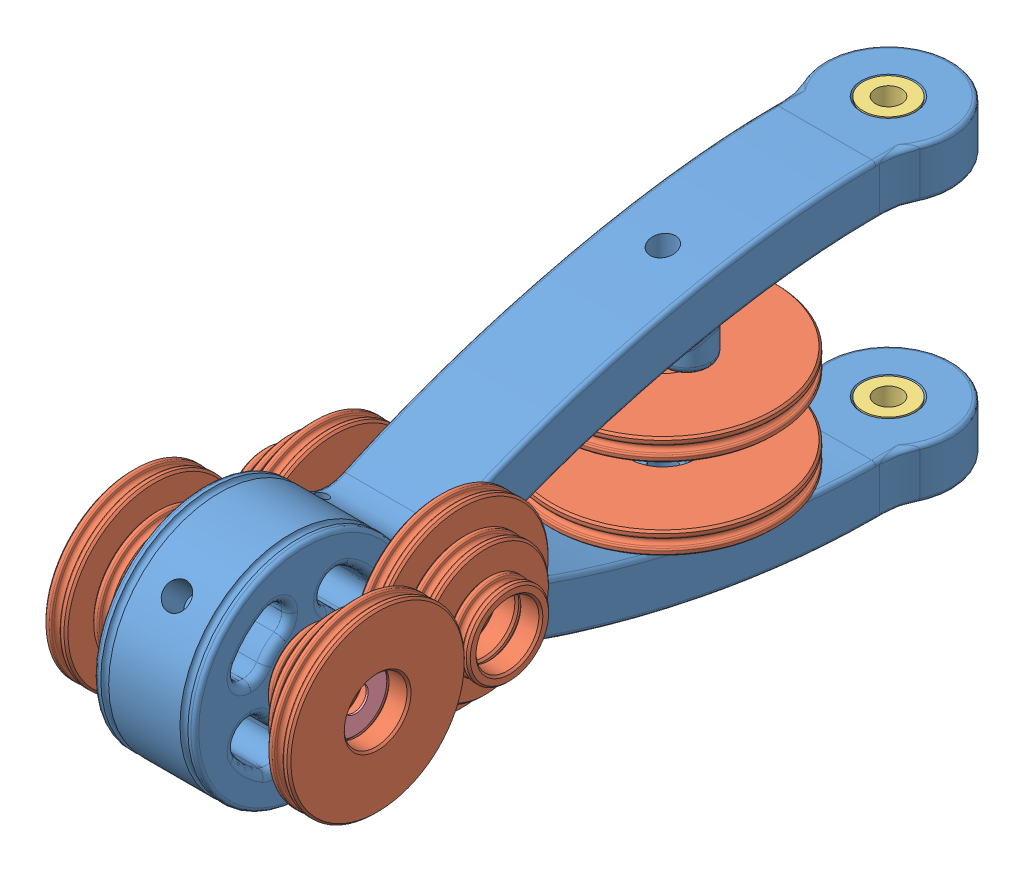
SolidWorks assembly Assem3^assembled_4dof_arm, configuration Default. Lengths in mm.
Overall size (34.5 42.48 102.6).
23 component instances, 4 part files, 25 mates.
Components (placement in the parent):
- joint1-1: joint1 [Default] at origin size (16 42.48 102)
- Pulley_configurable-1: Pulley_configurable [p1_bearing] at (8.0161 0 -16.65) x (0 -0.797414 -0.603433) z (0 0.603433 -0.797414) size (22.4 2.78 22.4)
- Pulley_configurable-3: Pulley_configurable [p2_bearing] at (11.0482 0 -16.65) x (0 0.936654 0.350255) z (0 -0.350255 0.936654) size (16.4 2.78 16.4)
- Pulley_configurable-6: Pulley_configurable [p3_bearing] at (14.0803 0 -16.65) x (0 0.732668 0.680586) z (0 -0.680586 0.732668) size (10.4 2.78 10.4)
- Pulley_configurable-7: Pulley_configurable [p3_bearing] at (8.0161 0 0) x (0 -0.534541 0.845142) z (0 -0.845142 -0.534541) size (10.4 2.78 10.4)
- Pulley_configurable-8: Pulley_configurable [p2_bearing] at (11.0482 0 0) x (0 0.972645 0.232297) z (0 -0.232297 0.972645) size (16.4 2.78 16.4)
- Pulley_configurable-9: Pulley_configurable [p1_bearing] at (14.0803 0 0) x (0 0.377137 0.926157) z (0 -0.926157 0.377137) size (22.4 2.78 22.4)
- 6377K490_ULTRA-LOW-FRICTION DRY-RUNNING SLEEVE BEARING-1: 6377K490_ULTRA-LOW-FRICTION DRY-RUNNING SLEEVE BEARING [6377K49] at (0 16.425 -80) x (1 0 0) z (0 -1 0) size (6.38 6.38 6.35)
- 6377K490_ULTRA-LOW-FRICTION DRY-RUNNING SLEEVE BEARING-2: 6377K490_ULTRA-LOW-FRICTION DRY-RUNNING SLEEVE BEARING [6377K49] at (0 -16.425 -80) x (1 0 0) z (0 -1 0) size (6.38 6.38 6.35)
- Pulley_configurable-13: Pulley_configurable [p0_bearing] at (0 5.1069 -51.5) x (0.969458 0 0.245256) z (-0.245256 0 0.969458) size (28.4 2.78 28.4)
- Pulley_configurable-14: Pulley_configurable [p0_bearing] at (0 -5.1069 -51.5) x (0.969458 0 0.245256) z (-0.245256 0 0.969458) size (28.4 2.78 28.4)
- 10thouspacer_3125shaft-1: 10thouspacer_3125shaft [Default] at (9.4051 0 0) x (0 -0.052278 -0.998633) z (1 0 0) size (7.87 7.87 0.25)
- 10thouspacer_3125shaft-2: 10thouspacer_3125shaft [Default] at (12.4373 0 0) x (0 -0.167406 -0.985888) z (1 0 0) size (7.87 7.87 0.25)
- 10thouspacer_3125shaft-3: 10thouspacer_3125shaft [Default] at (6.373 0 0) x (0 -0.167406 -0.985888) z (1 0 0) size (7.87 7.87 0.25)
- Pulley_configurable-15: Pulley_configurable [p1_bearing] at (-14.0803 0 0) x (0 0.377137 0.926157) z (0 0.926157 -0.377137) size (22.4 2.78 22.4)
- Pulley_configurable-16: Pulley_configurable [p3_bearing] at (-14.0803 0 -16.65) x (0 0.732668 0.680586) z (0 0.680586 -0.732668) size (10.4 2.78 10.4)
- Pulley_configurable-17: Pulley_configurable [p2_bearing] at (-11.0482 0 0) x (0 0.972645 0.232297) z (0 0.232297 -0.972645) size (16.4 2.78 16.4)
- Pulley_configurable-18: Pulley_configurable [p2_bearing] at (-11.0482 0 -16.65) x (0 0.936654 0.350255) z (0 0.350255 -0.936654) size (16.4 2.78 16.4)
- Pulley_configurable-19: Pulley_configurable [p1_bearing] at (-8.0161 0 -16.65) x (0 -0.797414 -0.603433) z (0 -0.603433 0.797414) size (22.4 2.78 22.4)
- Pulley_configurable-20: Pulley_configurable [p3_bearing] at (-8.0161 0 0) x (0 -0.534541 0.845142) z (0 0.845142 0.534541) size (10.4 2.78 10.4)
- 10thouspacer_3125shaft-4: 10thouspacer_3125shaft [Default] at (-12.6913 0 0) x (0 -0.167406 -0.985888) z (1 0 0) size (7.87 7.87 0.25)
- 10thouspacer_3125shaft-5: 10thouspacer_3125shaft [Default] at (-9.6591 0 0) x (0 -0.052278 -0.998633) z (1 0 0) size (7.87 7.87 0.25)
- 10thouspacer_3125shaft-6: 10thouspacer_3125shaft [Default] at (-6.627 0 0) x (0 -0.167406 -0.985888) z (1 0 0) size (7.87 7.87 0.25)
Mates (geometry in assembly coordinates):
- Concentric20: concentric: cylinder of joint1-1 through (6.373 0 -16.65) axis (-1 0 0) radius 1.5875; cylinder of Pulley_configurable-6 through (14.0803 0 -16.65) axis (1 0 0) radius 3.9688
- Concentric21: concentric: cylinder of joint1-1 through (6.373 0 0) axis (-1 0 0) radius 1.5875; cylinder of Pulley_configurable-9 through (14.0803 0 0) axis (1 0 0) radius 3.9688
- Concentric31: concentric: cylinder of joint1-1 through (0 19.6 -80) axis (0 -1 0) radius 3.175; cylinder of 6377K490_ULTRA-LOW-FRICTION DRY-RUNNING SLEEVE BEARING-1 through (0 13.25 -80) axis (0 1 0) radius 3.1877
- Concentric32: concentric: cylinder of joint1-1 through (0 -19.6 -80) axis (0 1 0) radius 3.175; cylinder of 6377K490_ULTRA-LOW-FRICTION DRY-RUNNING SLEEVE BEARING-2 through (0 -19.6 -80) axis (0 1 0) radius 3.1877
- Concentric62: concentric: cylinder of joint1-1 through (0 -19.602 -51.5) axis (0 1 0) radius 1.5875; cylinder of Pulley_configurable-13 through (0 5.1069 -51.5) axis (0 -1 0) radius 3.9688
- Concentric3: concentric: cylinder of Pulley_configurable-1 through (8.0161 0 -16.65) axis (1 0 0) radius 3.9688; cylinder of Pulley_configurable-3 through (11.0482 0 -16.65) axis (1 0 0) radius 3.9688
- Concentric4: concentric: cylinder of Pulley_configurable-3 through (11.0482 0 -16.65) axis (1 0 0) radius 3.9688; cylinder of Pulley_configurable-6 through (14.0803 0 -16.65) axis (1 0 0) radius 3.9688
- Concentric11: concentric: cylinder of Pulley_configurable-7 through (8.0161 0 0) axis (1 0 0) radius 3.9688; cylinder of Pulley_configurable-8 through (11.0482 0 0) axis (1 0 0) radius 3.9688
- Concentric10: concentric: cylinder of Pulley_configurable-8 through (11.0482 0 0) axis (1 0 0) radius 3.9688; cylinder of Pulley_configurable-9 through (14.0803 0 0) axis (1 0 0) radius 3.9688
- Concentric57: concentric: cylinder of Pulley_configurable-13 through (0 5.1069 -51.5) axis (0 -1 0) radius 3.9688; cylinder of Pulley_configurable-14 through (0 -5.1069 -51.5) axis (0 -1 0) radius 3.9688
- Coincident30: coincident: plane of joint1-1 through (0 0 0) normal (0 0 1); plane of assembly through (0 0 0) normal (0 0 1)
- Coincident31: coincident: plane of joint1-1 through (0 0 0) normal (0 1 0); plane of assembly through (0 0 0) normal (0 1 0)
- Coincident32: coincident: plane of joint1-1 through (0 0 0) normal (1 0 0); plane of assembly through (0 0 0) normal (1 0 0)
- Coincident33: coincident: plane of Pulley_configurable-6 through (15.4694 0 -16.65) normal (1 0 0); plane of Pulley_configurable-9 through (15.4694 0 0) normal (1 0 0)
- Coincident34: coincident: plane of Pulley_configurable-3 through (12.4373 0 -16.65) normal (1 0 0); plane of Pulley_configurable-8 through (12.4373 0 0) normal (1 0 0)
- Coincident35: coincident: plane of Pulley_configurable-1 through (9.4051 0 -16.65) normal (1 0 0); plane of Pulley_configurable-7 through (9.4051 0 0) normal (1 0 0)
- Concentric63: concentric: cylinder of Pulley_configurable-9 through (14.0803 0 0) axis (1 0 0) radius 3.9688; cylinder of 10thouspacer_3125shaft-1 through (9.6591 0 0) axis (-1 0 0) radius 1.6002
- Concentric64: concentric: cylinder of 10thouspacer_3125shaft-1 through (9.6591 0 0) axis (-1 0 0) radius 1.6002; cylinder of 10thouspacer_3125shaft-2 through (12.6913 0 0) axis (-1 0 0) radius 1.6002
- Concentric65: concentric: cylinder of 10thouspacer_3125shaft-1 through (9.6591 0 0) axis (-1 0 0) radius 1.6002; cylinder of 10thouspacer_3125shaft-3 through (6.627 0 0) axis (-1 0 0) radius 1.6002
- Coincident39: coincident: plane of joint1-1 through (6.373 19.6 -88.002) normal (1 0 0); plane of 10thouspacer_3125shaft-3 through (6.373 0 0) normal (-1 0 0)
- Coincident40: coincident: plane of Pulley_configurable-7 through (6.627 0 0) normal (-1 0 0); plane of 10thouspacer_3125shaft-3 through (6.627 0 0) normal (1 0 0)
- Coincident41: coincident: plane of Pulley_configurable-7 through (9.4051 0 0) normal (1 0 0); plane of 10thouspacer_3125shaft-1 through (9.4051 0 0) normal (-1 0 0)
- Coincident42: coincident: plane of Pulley_configurable-8 through (9.6591 0 0) normal (-1 0 0); plane of 10thouspacer_3125shaft-1 through (9.6591 0 0) normal (1 0 0)
- Coincident43: coincident: plane of Pulley_configurable-8 through (12.4373 0 0) normal (1 0 0); plane of 10thouspacer_3125shaft-2 through (12.4373 0 0) normal (-1 0 0)
- Coincident44: coincident: plane of Pulley_configurable-9 through (12.6913 0 0) normal (-1 0 0); plane of 10thouspacer_3125shaft-2 through (12.6913 0 0) normal (1 0 0)
